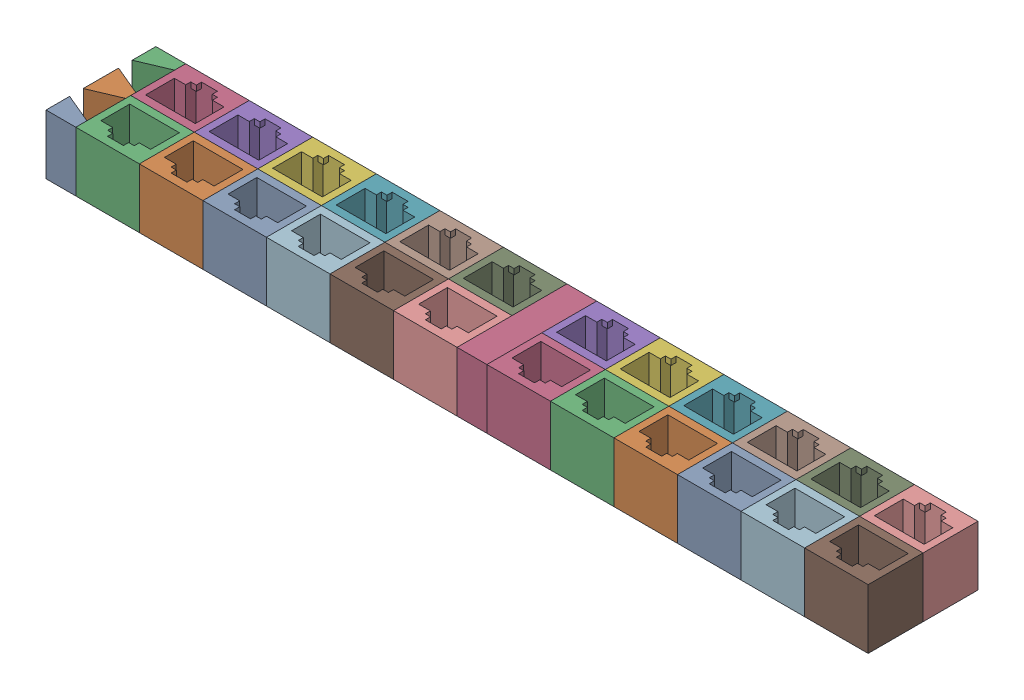
SolidWorks assembly 24-port 12-group block - half 2, configuration Default. Lengths in mm.
Overall size (207 15 27.66).
32 component instances, 3 part files, 9 mates.
Components (placement in the parent):
- RJ45 spacer block positive-1: RJ45 spacer block positive [Default] at (6.2573 -7.9228 22.985) size (7.5 15 27.66)
- 12-port block-1: 12-port block [Default] at (39.4189 -31.648 -42.9155) size (96 15 27.66)
  - 6-port block-1: 6-port block [Default] at (18.7671 16.9181 15.9423) size (96 15 13.83)
    - RJ45 dummy jack trimmed-1: RJ45 dummy jack trimmed [Default] at (-42.6786 6.807 34.1283) size (16 15 13.83)
    - RJ45 dummy jack trimmed-2: RJ45 dummy jack trimmed [Default] at (-26.6786 6.807 34.1283) size (16 15 13.83)
    - RJ45 dummy jack trimmed-3: RJ45 dummy jack trimmed [Default] at (-10.6786 6.807 34.1283) size (16 15 13.83)
    - RJ45 dummy jack trimmed-4: RJ45 dummy jack trimmed [Default] at (5.3214 6.807 34.1283) size (16 15 13.83)
    - RJ45 dummy jack trimmed-5: RJ45 dummy jack trimmed [Default] at (21.3214 6.807 34.1283) size (16 15 13.83)
    - RJ45 dummy jack trimmed-6: RJ45 dummy jack trimmed [Default] at (37.3214 6.807 34.1283) size (16 15 13.83)
  - 6-port block-2: 6-port block [Default] at (25.9098 16.9181 88.1988) x (-1 0 0) z (0 0 -1) size (96 15 13.83)
    - RJ45 dummy jack trimmed-1: RJ45 dummy jack trimmed [Default] at (-42.6786 6.807 34.1283) size (16 15 13.83)
    - RJ45 dummy jack trimmed-2: RJ45 dummy jack trimmed [Default] at (-26.6786 6.807 34.1283) size (16 15 13.83)
    - RJ45 dummy jack trimmed-3: RJ45 dummy jack trimmed [Default] at (-10.6786 6.807 34.1283) size (16 15 13.83)
    - RJ45 dummy jack trimmed-4: RJ45 dummy jack trimmed [Default] at (5.3214 6.807 34.1283) size (16 15 13.83)
    - RJ45 dummy jack trimmed-5: RJ45 dummy jack trimmed [Default] at (21.3214 6.807 34.1283) size (16 15 13.83)
    - RJ45 dummy jack trimmed-6: RJ45 dummy jack trimmed [Default] at (37.3214 6.807 34.1283) size (16 15 13.83)
- RJ45 spacer block-1: RJ45 spacer block [Default] at (109.7573 -7.9228 22.985) size (7.5 15 27.66)
- 12-port block-2: 12-port block [Default] at (142.9189 -31.648 -42.9155) size (96 15 27.66)
  - 6-port block-1: 6-port block [Default] at (18.7671 16.9181 15.9423) size (96 15 13.83)
    - RJ45 dummy jack trimmed-1: RJ45 dummy jack trimmed [Default] at (-42.6786 6.807 34.1283) size (16 15 13.83)
    - RJ45 dummy jack trimmed-2: RJ45 dummy jack trimmed [Default] at (-26.6786 6.807 34.1283) size (16 15 13.83)
    - RJ45 dummy jack trimmed-3: RJ45 dummy jack trimmed [Default] at (-10.6786 6.807 34.1283) size (16 15 13.83)
    - RJ45 dummy jack trimmed-4: RJ45 dummy jack trimmed [Default] at (5.3214 6.807 34.1283) size (16 15 13.83)
    - RJ45 dummy jack trimmed-5: RJ45 dummy jack trimmed [Default] at (21.3214 6.807 34.1283) size (16 15 13.83)
    - RJ45 dummy jack trimmed-6: RJ45 dummy jack trimmed [Default] at (37.3214 6.807 34.1283) size (16 15 13.83)
  - 6-port block-2: 6-port block [Default] at (25.9098 16.9181 88.1988) x (-1 0 0) z (0 0 -1) size (96 15 13.83)
    - RJ45 dummy jack trimmed-1: RJ45 dummy jack trimmed [Default] at (-42.6786 6.807 34.1283) size (16 15 13.83)
    - RJ45 dummy jack trimmed-2: RJ45 dummy jack trimmed [Default] at (-26.6786 6.807 34.1283) size (16 15 13.83)
    - RJ45 dummy jack trimmed-3: RJ45 dummy jack trimmed [Default] at (-10.6786 6.807 34.1283) size (16 15 13.83)
    - RJ45 dummy jack trimmed-4: RJ45 dummy jack trimmed [Default] at (5.3214 6.807 34.1283) size (16 15 13.83)
    - RJ45 dummy jack trimmed-5: RJ45 dummy jack trimmed [Default] at (21.3214 6.807 34.1283) size (16 15 13.83)
    - RJ45 dummy jack trimmed-6: RJ45 dummy jack trimmed [Default] at (37.3214 6.807 34.1283) size (16 15 13.83)
Mates (geometry in assembly coordinates):
- Coincident1: coincident anti-aligned: plane of 12-port block-1/6-port block-2/RJ45 dummy jack trimmed-1 through (109.7573 17.0772 22.985) normal (1 0 0); plane of RJ45 spacer block-1 through (109.7573 17.0772 22.985) normal (-1 0 0)
- Coincident2: coincident: point of 12-port block-1/6-port block-2/RJ45 dummy jack trimmed-1; moEndPointRef_w of RJ45 spacer block-1
- Coincident3: coincident: unknown of 12-port block-1/6-port block-1/RJ45 dummy jack trimmed-6; unknown of RJ45 spacer block-1
- Coincident4: coincident anti-aligned: plane of RJ45 spacer block-1 through (117.2573 17.0772 22.985) normal (1 0 0); plane of 12-port block-2/6-port block-2/RJ45 dummy jack trimmed-6 through (117.2573 17.0772 22.985) normal (-1 0 0)
- Coincident5: coincident: unknown of RJ45 spacer block-1; unknown of 12-port block-2/6-port block-1/RJ45 dummy jack trimmed-1
- Coincident6: coincident: unknown of RJ45 spacer block-1; unknown of 12-port block-2/6-port block-1/RJ45 dummy jack trimmed-1
- Coincident7: coincident anti-aligned: plane of RJ45 spacer block positive-1 through (13.7573 17.0772 22.985) normal (1 0 0); plane of 12-port block-1/6-port block-1/RJ45 dummy jack trimmed-1 through (13.7573 17.0772 -4.675) normal (-1 0 0)
- Coincident8: coincident: unknown of RJ45 spacer block positive-1; unknown of 12-port block-1/6-port block-1/RJ45 dummy jack trimmed-1
- Coincident9: coincident: unknown of RJ45 spacer block positive-1; unknown of 12-port block-1/6-port block-1/RJ45 dummy jack trimmed-1
